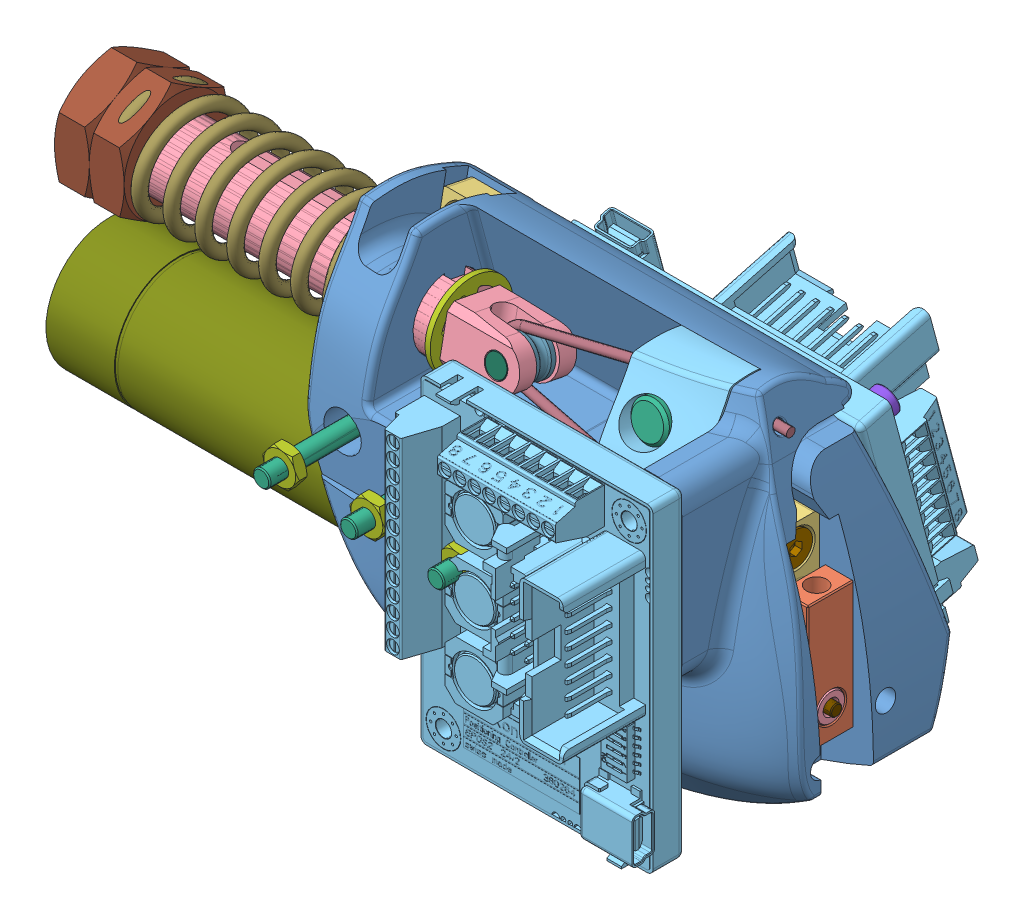
SolidWorks assembly a-antriebstrang-bein-rechts-v05, configuration Slave-BoardPosition 2. Lengths in mm.
Overall size (130.8 65.2 78.85).
43 component instances, 26 part files, 38 mates.
Components (placement in the parent):
- a-motorträger-beine-rechts-v01-1: a-motorträger-beine-rechts-v01 [01] x (-1 0 0) z (0 0 -1) size (130.38 65.2 41.28)
  - p-halterreferenz-rechts-v04-1: p-halterreferenz-rechts-v04 [01] at (-8 0 0) x (0 0 -1) z (1 0 0) size (41.28 65.2 84.36)
  - z-jfm-0608-06-v01-1: z-jfm-0608-06-v01 [01] at (-23.3 0 0) x (-1 0 0) z (0 0 -1) size (6 12 12)
  - z-induktiv-sensor-v01-1: z-induktiv-sensor-v01 [01] at (29 21.9082 7.6275) x (1 0 0) z (0 0.190809 -0.981627) size (8 16 4.7)
  - z-induktiv-sensor-v01-2: z-induktiv-sensor-v01 [01] at (-25.5 8.63 4) x (0 0 -1) z (-1 0 0) size (8 16 4.7)
  - p-federstössel-v01-1: p-federstössel-v01 [01] at (77.9 27.8 -1.72) x (-1 0 0) z (0 -0.190809 0.981627) size (77 12 12)
  - p-halterdeckel-rechts-v02-1: p-halterdeckel-rechts-v02 [01] at (-8 0 0) x (0 0 -1) z (1 0 0) size (28.27 33.45 14.71)
  - z-passschraube-misumi-4-v01-1: z-passschraube-misumi-4-v01 [01] at (-13.1 35.2829 -8.5672) x (0 -0.190809 0.981627) z (-0.839411 -0.533511 -0.103704) size (18 6.5 6.5)
  - z-passschraube-misumi-4-v01-2: z-passschraube-misumi-4-v01 [01] at (-13.1 16.1412 -12.288) x (0 -0.190809 0.981627) z (-0.58333 0.797312 0.154982) size (18 6.5 6.5)
  - Lock washer DIN 6799 - 7-11: Lock washer DIN 6799 - 7 [Lock washer DIN 6799 - 7] at (24 27.8 -1.72) x (0 0 1) z (-1 0 0) size (14.3 11.94 0.9)
  - Hexagon Nut ISO 4032 - M2.5 - W - N-19: Hexagon Nut ISO 4032 - M2.5 - W - N [Hexagon Nut ISO 4032 - M2.5 - W - N] at (-13.1 31.8991 8.8409) x (1 0 0) z (0 -0.190809 0.981627) size (5 5.77 2)
  - Hexagon Nut ISO 4032 - M2.5 - W - N-20: Hexagon Nut ISO 4032 - M2.5 - W - N [Hexagon Nut ISO 4032 - M2.5 - W - N] at (-13.1 12.7574 5.1202) x (1 0 0) z (0 -0.190809 0.981627) size (5 5.77 2)
  - DIN 7991 - M3 x 8 --- 4.8C-19: DIN 7991 - M3 x 8 --- 4.8C [DIN 7991 - M3 x 8 --- 4.8C] at (-30.15 20.63 0) size (8 5.7 5.7)
  - DIN 7991 - M3 x 8 --- 4.8C-20: DIN 7991 - M3 x 8 --- 4.8C [DIN 7991 - M3 x 8 --- 4.8C] at (33 34.5749 5.3527) x (0 -0.190809 0.981627) z (-0.981627 0.187303 0.036408) size (8 5.7 5.7)
  - p-oese-v01-1: p-oese-v01 [01] at (-25.5 37.4 0) size (3.5 4 4)
  - Hexagon Thin Nut ISO 4035 - M12 - N-19: Hexagon Thin Nut ISO 4035 - M12 - N [Hexagon Thin Nut ISO 4035 - M12 - N] at (74.9 27.8 -1.72) x (0 -0.006521 -0.999979) z (-1 0 0) size (18 20.78 6)
  - Hexagon Thin Nut ISO 4035 - M12 - N-20: Hexagon Thin Nut ISO 4035 - M12 - N [Hexagon Thin Nut ISO 4035 - M12 - N] at (80.9 27.8 -1.72) x (0 0 1) z (-1 0 0) size (18 20.78 6)
  - z-feder-febrotec-v01-1: z-feder-febrotec-v01 [01] at (40 28.171 -1.6479) x (1 0 0) z (0 -0.190809 0.981627) size (40.25 20.98 20.5)
  - p-seil-v02-1: p-seil-v02 [01] at (-16.85 -0.1381 -7.1506) x (-1 0 0) z (0 0.190809 -0.981627) size (48.5 39 1.5)
  - p-umlenkpulley-v06-1: p-umlenkpulley-v06 [01] at (-13.1 33.728 -0.5677) x (0 -0.190809 0.981627) z (-0.981627 0.187303 0.036408) size (3.6 7.15 7.15)
  - p-umlenkpulley-v06-4: p-umlenkpulley-v06 [01] at (-13.1 14.5863 -4.2885) x (0 -0.190809 0.981627) z (-0.997632 0.067518 0.013124) size (3.6 7.15 7.15)
  - p-umlenkpulley-v06-3: p-umlenkpulley-v06 [01] at (14.9 27.8 -1.72) x (0 -0.190809 0.981627) z (-0.981627 0.187303 0.036408) size (3.6 7.15 7.15)
  - Parallel Pin ISO 2338 - 4 h6 x 10 - St-11: Parallel Pin ISO 2338 - 4 h6 x 10 - St [Parallel Pin ISO 2338 - 4 h6 x 10 - St] at (14.9 28.754 -6.6281) x (0 -0.190809 0.981627) z (-0.981627 0.187303 0.036408) size (10 4 4)
- a-Maxon-EC22-386675-v01-2: a-Maxon-EC22-386675-v01 [01] at (-25.4 0 0) x (-1 0 0) z (0 0.342022 -0.939692) size (103.18 22 22)
  - z-Motor-Maxon-EC22-386673-v01-1: z-Motor-Maxon-EC22-386673-v01 [01] at origin size (73.23 22 22)
  - z-Getriebe-Maxon-GP22C_1-STUFIG-143972-v01-1: z-Getriebe-Maxon-GP22C_1-STUFIG-143972-v01 [01] at (-25.4 0 0) size (40.25 22 22)
- p-motorpulley-v04-2: p-motorpulley-v04 [01] at (3.15 0 0) x (1 0 0) z (0 0.939692 0.342022) size (35.05 9 9)
- DIN 913 - M2 x 3-C-10: DIN 913 - M2 x 3-C [DIN 913 - M2 x 3-C] at (10.15 4.2286 1.5391) x (0 -0.939692 -0.342022) z (1 0 0) size (3 2 2)
- p-absolutmess-plättchen-v04-2: p-absolutmess-plättchen-v04 [01] at (36.2 0 0) x (0 0 1) z (-1 0 0) size (8 22 5)
- ISO 2010 - M2.5 x 10 --- 10C-29: ISO 2010 - M2.5 x 10 --- 10C [ISO 2010 - M2.5 x 10 --- 10C] at (9 6.5778 2.3941) x (-1 0 0) z (0 -0.859497 -0.51114) size (10.59 4.7 4.66)
- ISO 2010 - M2.5 x 10 --- 10C-30: ISO 2010 - M2.5 x 10 --- 10C [ISO 2010 - M2.5 x 10 --- 10C] at (9 -5.3623 4.4995) x (-1 0 0) z (0 -0.924225 -0.381849) size (10.59 4.7 4.66)
- ISO 2010 - M2.5 x 10 --- 10C-31: ISO 2010 - M2.5 x 10 --- 10C [ISO 2010 - M2.5 x 10 --- 10C] at (9 -1.2155 -6.8937) x (-1 0 0) z (0 -0.959089 0.283105) size (10.59 4.7 4.66)
- p-gewindeeinsatz-v01-1: p-gewindeeinsatz-v01 [01] at (30.2 0 0) x (1 0 0) z (0 -0.998486 -0.054998) size (6 5 5)
- z-380264_epos2_24_2-v01-3: z-380264_epos2_24_2-v01 [01] at (9 10.5 22) x (0 1 0) z (1 0 0) size (55.21 20.01 40.39)
- z-380264_epos2_24_2-v01-2: z-380264_epos2_24_2-v01 [01] at (2 14.1149 -20.6087) x (1 0 0) z (0 0.965926 0.258819) size (55.21 20.01 40.39)
- z-zyl-schr-schaft-M3x40-v01-4: z-zyl-schr-schaft-M3x40-v01 [01] at (-2 15 -13) x (0 0 1) z (0.955009 0.296577 0) size (43 5.5 5.5)
- Hexagon Thin Nut ISO 4035 - M3 - C-11: Hexagon Thin Nut ISO 4035 - M3 - C [Hexagon Thin Nut ISO 4035 - M3 - C] at (-2 15 25) x (0.923728 0.383049 0) z (0 0 -1) size (5.5 6.35 1.8)
- z-zyl-schr-schaft-M3x40-v01-5: z-zyl-schr-schaft-M3x40-v01 [01] at (-17 15 -13) x (0 0 1) z (0.955009 0.296577 0) size (43 5.5 5.5)
- z-zyl-schr-schaft-M3x40-v01-6: z-zyl-schr-schaft-M3x40-v01 [01] at (-32 15 -13) x (0 0 1) z (0.955009 0.296577 0) size (43 5.5 5.5)
- Hexagon Thin Nut ISO 4035 - M3 - C-19: Hexagon Thin Nut ISO 4035 - M3 - C [Hexagon Thin Nut ISO 4035 - M3 - C] at (-17 15 25) x (0.923728 0.383049 0) z (0 0 -1) size (5.5 6.35 1.8)
- Hexagon Thin Nut ISO 4035 - M3 - C-20: Hexagon Thin Nut ISO 4035 - M3 - C [Hexagon Thin Nut ISO 4035 - M3 - C] at (-32 15 25) x (0.923728 0.383049 0) z (0 0 -1) size (5.5 6.35 1.8)
- n-zyl-schr-i6kt-M2.5x8 (BN11)-3: n-zyl-schr-i6kt-M2.5x8 (BN11) [n-zyl-schr-i6kt-M2.5x8 (BN11)] at (-21.5 -0.2788 -28.7101) x (0 -0.258819 0.965926) z (-0.965926 0.25 0.066987) size (10.5 4.5 4.5)
- n-zyl-schr-i6kt-M2.5x8 (BN11)-4: n-zyl-schr-i6kt-M2.5x8 (BN11) [n-zyl-schr-i6kt-M2.5x8 (BN11)] at (25.5 30.6309 -20.4279) x (0 -0.258819 0.965926) z (-0.793112 0.588322 0.15764) size (10.5 4.5 4.5)
Mates (geometry in assembly coordinates):
- Konzentrisch1: concentric aligned: cylinder of a-motorträger-beine-rechts-v01-1/p-halterreferenz-rechts-v04-1 through (0 0 0) axis (-1 0 0) radius 11.5; cylinder of a-Maxon-EC22-386675-v01-2/z-Getriebe-Maxon-GP22C_1-STUFIG-143972-v01-1 through (0 0 0) axis (-1 0 0) radius 11
- Deckungsgleich1: coincident anti-aligned: plane of a-motorträger-beine-rechts-v01-1/p-halterreferenz-rechts-v04-1 through (0 0 0) normal (-1 0 0); plane of a-Maxon-EC22-386675-v01-2/z-Getriebe-Maxon-GP22C_1-STUFIG-143972-v01-1 through (0 0 0) normal (1 0 0)
- Deckungsgleich2: coincident anti-aligned: plane of a-motorträger-beine-rechts-v01-1 through (0 0 0) normal (0 0 -1); plane of assembly through (0 0 0) normal (0 0 1)
- Deckungsgleich3: coincident aligned: plane of a-motorträger-beine-rechts-v01-1; plane of assembly through (0 0 0) normal (0 1 0)
- Deckungsgleich4: coincident anti-aligned: plane of a-motorträger-beine-rechts-v01-1 through (0 0 0) normal (-1 0 0); plane of assembly through (0 0 0) normal (1 0 0)
- Konzentrisch2: concentric aligned: cylinder of a-Maxon-EC22-386675-v01-2/z-Getriebe-Maxon-GP22C_1-STUFIG-143972-v01-1 through (14.85 0 0) axis (-1 0 0) radius 2; cylinder of p-motorpulley-v04-2 through (3.15 0 0) axis (-1 0 0) radius 2
- Deckungsgleich5: coincident anti-aligned: plane of a-Maxon-EC22-386675-v01-2/z-Getriebe-Maxon-GP22C_1-STUFIG-143972-v01-1 through (3.15 0 0) normal (1 0 0); plane of p-motorpulley-v04-2 through (3.15 1.5391 -4.2286) normal (-1 0 0)
- Konzentrisch3: concentric anti-aligned: cylinder of p-motorpulley-v04-2 through (10.15 0 0) axis (0 -0.939692 -0.342022) radius 0.8; cylinder of DIN 913 - M2 x 3-C-10 through (10.15 16.1627 5.8828) axis (0 0.939692 0.342022) radius 1
- Parallel2: parallel aligned: plane of a-Maxon-EC22-386675-v01-2/z-Getriebe-Maxon-GP22C_1-STUFIG-143972-v01-1 through (10.2 1.4095 0.513) normal (0 0.939692 0.342022); plane of p-motorpulley-v04-2 through (3.15 0 0) normal (0 0.939692 0.342022)
- Deckungsgleich7: coincident anti-aligned: plane of a-Maxon-EC22-386675-v01-2/z-Getriebe-Maxon-GP22C_1-STUFIG-143972-v01-1 through (10.2 1.4095 0.513) normal (0 0.939692 0.342022); plane of DIN 913 - M2 x 3-C-10 through (10.15 1.5805 0.0432) normal (0 -0.939692 -0.342022)
- Parallel3: parallel anti-aligned: plane of a-motorträger-beine-rechts-v01-1/p-halterreferenz-rechts-v04-1 through (42 0 -4.5) normal (0 0 1); plane of p-absolutmess-plättchen-v04-2 through (31.2 -5 -4) normal (0 0 -1)
- Abstand1: distance = 1 mm anti-aligned: plane of a-motorträger-beine-rechts-v01-1/z-induktiv-sensor-v01-2 through (30.2 8.63 -4) normal (1 0 0); plane of p-absolutmess-plättchen-v04-2 through (31.2 0 0) normal (-1 0 0)
- Konzentrisch5: concentric anti-aligned: cylinder of p-motorpulley-v04-2 through (3.15 0 0) axis (-1 0 0) radius 1; cylinder of p-absolutmess-plättchen-v04-2 through (31.2 0 0) axis (1 0 0) radius 2.5
- Konzentrisch6: concentric aligned: cylinder of a-motorträger-beine-rechts-v01-1/p-halterreferenz-rechts-v04-1 through (-42.3814 -5.3623 4.4995) axis (1 0 0) radius 1.5; cylinder of a-Maxon-EC22-386675-v01-2/z-Getriebe-Maxon-GP22C_1-STUFIG-143972-v01-1 through (-4 -5.3623 4.4995) axis (1 0 0) radius 1.025
- Konzentrisch29: concentric aligned: cylinder of a-motorträger-beine-rechts-v01-1/p-halterreferenz-rechts-v04-1 through (-42.3814 -5.3623 4.4995) axis (1 0 0) radius 1.5; cylinder of ISO 2010 - M2.5 x 10 --- 10C-30 through (24.875 -5.3623 4.4995) axis (1 0 0) radius 1.25
- Deckungsgleich16: coincident aligned: cone of a-motorträger-beine-rechts-v01-1/p-halterreferenz-rechts-v04-1 through (8 -5.3623 4.4995) axis (-1 0 0); cone of ISO 2010 - M2.5 x 10 --- 10C-30 through (8 -5.3623 4.4995) axis (-1 0 0)
- Konzentrisch31: concentric aligned: cylinder of a-motorträger-beine-rechts-v01-1/p-halterreferenz-rechts-v04-1 through (-42.3814 6.5778 2.3941) axis (1 0 0) radius 1.5; cylinder of ISO 2010 - M2.5 x 10 --- 10C-29 through (24.875 6.5778 2.3941) axis (1 0 0) radius 1.25
- Deckungsgleich17: coincident aligned: cone of a-motorträger-beine-rechts-v01-1/p-halterreferenz-rechts-v04-1 through (8 6.5778 2.3941) axis (-1 0 0); cone of ISO 2010 - M2.5 x 10 --- 10C-29 through (8 6.5778 2.3941) axis (-1 0 0)
- Konzentrisch33: concentric aligned: cylinder of a-motorträger-beine-rechts-v01-1/p-halterreferenz-rechts-v04-1 through (-42.3814 -1.2155 -6.8937) axis (1 0 0) radius 1.5; cylinder of ISO 2010 - M2.5 x 10 --- 10C-31 through (24.875 -1.2155 -6.8937) axis (1 0 0) radius 1.25
- Deckungsgleich18: coincident aligned: cone of a-motorträger-beine-rechts-v01-1/p-halterreferenz-rechts-v04-1 through (8 -1.2155 -6.8937) axis (-1 0 0); cone of ISO 2010 - M2.5 x 10 --- 10C-31 through (8 -1.2155 -6.8937) axis (-1 0 0)
- Konzentrisch318: concentric anti-aligned: cylinder of p-absolutmess-plättchen-v04-2 through (31.2 0 0) axis (1 0 0) radius 2.5; cylinder of p-gewindeeinsatz-v01-1 through (30.2 0 0) axis (-1 0 0) radius 2.5
- Deckungsgleich150: coincident aligned: plane of p-absolutmess-plättchen-v04-2 through (36.2 0 0) normal (1 0 0); plane of p-gewindeeinsatz-v01-1 through (36.2 -0.0275 0.4992) normal (1 0 0)
- Konzentrisch324: concentric anti-aligned: cylinder of a-motorträger-beine-rechts-v01-1/p-halterreferenz-rechts-v04-1 through (-2 15 -22.5327) axis (0 0 -1) radius 2; cylinder of z-zyl-schr-schaft-M3x40-v01-4 through (-2 15 12) axis (0 0 1) radius 1.5
- Deckungsgleich162: coincident anti-aligned: plane of a-motorträger-beine-rechts-v01-1/p-halterreferenz-rechts-v04-1 through (0 15 9) normal (0 0 1); plane of z-zyl-schr-schaft-M3x40-v01-4
- Konzentrisch325: concentric aligned: cylinder of z-zyl-schr-schaft-M3x40-v01-4 through (-2 15 -13) axis (0 0 -1) radius 1.5; cylinder of Hexagon Thin Nut ISO 4035 - M3 - C-11 through (-2 15 26.8) axis (0 0 -1) radius 1.25
- Abstand2: distance = 35 mm anti-aligned: plane of Hexagon Thin Nut ISO 4035 - M3 - C-11 through (-7.0805 12.8932 25) normal (0 0 -1); plane of z-zyl-schr-schaft-M3x40-v01-4 through (-1.1844 12.3737 -10) normal (0 0 1)
- Konzentrisch326: concentric aligned: cylinder of a-motorträger-beine-rechts-v01-1/p-halterreferenz-rechts-v04-1 through (-2 15 -22.5327) axis (0 0 -1) radius 2; cylinder of z-zyl-schr-schaft-M3x40-v01-4 through (-2 15 -13) axis (0 0 -1) radius 1.5
- Deckungsgleich163: coincident anti-aligned: plane of a-motorträger-beine-rechts-v01-1/p-halterreferenz-rechts-v04-1 through (1.25 15 -10) normal (0 0 -1); plane of z-zyl-schr-schaft-M3x40-v01-4 through (-1.1844 12.3737 -10) normal (0 0 1)
- Deckungsgleich165: coincident anti-aligned: plane of z-380264_epos2_24_2-v01-2 through (2 13.0796 -16.745) normal (0 -0.258819 0.965926); plane of a-motorträger-beine-rechts-v01-1/p-halterreferenz-rechts-v04-1 through (8 5.0624 -18.8932) normal (0 0.258819 -0.965926)
- Konzentrisch327: concentric aligned: cylinder of a-motorträger-beine-rechts-v01-1/p-halterreferenz-rechts-v04-1 through (-21.5 -13.657 21.2181) axis (0 0.258819 -0.965926) radius 0.9; cylinder of z-380264_epos2_24_2-v01-2 through (-21.5 -0.9258 -26.2953) axis (0 0.258819 -0.965926) radius 1.35
- Konzentrisch328: concentric aligned: cylinder of a-motorträger-beine-rechts-v01-1/p-halterreferenz-rechts-v04-1 through (25.5 26.2089 -3.9248) axis (0 0.258819 -0.965926) radius 0.9; cylinder of z-380264_epos2_24_2-v01-2 through (25.5 29.9838 -18.0131) axis (0 0.258819 -0.965926) radius 1.35
- Deckungsgleich166: coincident anti-aligned: plane of a-motorträger-beine-rechts-v01-1/p-halterreferenz-rechts-v04-1 through (28.5 37.5 18) normal (0 0 1); plane of z-380264_epos2_24_2-v01-3 through (9 10.5 18) normal (0 0 -1)
- Konzentrisch329: concentric aligned: cylinder of a-motorträger-beine-rechts-v01-1/p-halterreferenz-rechts-v04-1 through (25 34 8) axis (0 0 1) radius 0.9; cylinder of z-380264_epos2_24_2-v01-3 through (25 34 23.6) axis (0 0 1) radius 1.35
- Konzentrisch330: concentric aligned: cylinder of a-motorträger-beine-rechts-v01-1/p-halterreferenz-rechts-v04-1 through (-7 -13 8) axis (0 0 1) radius 0.9; cylinder of z-380264_epos2_24_2-v01-3 through (-7 -13 23.6) axis (0 0 1) radius 1.35
- Konzentrisch331: concentric aligned: cylinder of z-380264_epos2_24_2-v01-2 through (25.5 29.9838 -18.0131) axis (0 0.258819 -0.965926) radius 1.35; cylinder of n-zyl-schr-i6kt-M2.5x8 (BN11)-4 through (25.5 38.8484 -51.0961) axis (0 0.258819 -0.965926) radius 1.25
- Deckungsgleich167: coincident anti-aligned: plane of z-380264_epos2_24_2-v01-2 through (25.5 29.9838 -18.0131) normal (0 0.258819 -0.965926); plane of n-zyl-schr-i6kt-M2.5x8 (BN11)-4 through (26.8704 31.7075 -17.5512) normal (0 -0.258819 0.965926)
- Konzentrisch332: concentric aligned: cylinder of z-380264_epos2_24_2-v01-2 through (-21.5 -0.9258 -26.2953) axis (0 0.258819 -0.965926) radius 1.35; cylinder of n-zyl-schr-i6kt-M2.5x8 (BN11)-3 through (-21.5 7.9387 -59.3783) axis (0 0.258819 -0.965926) radius 1.25
- Deckungsgleich168: coincident aligned: plane of z-380264_epos2_24_2-v01-2 through (-21.5 -0.9258 -26.2953) normal (0 0.258819 -0.965926); circle of n-zyl-schr-i6kt-M2.5x8 (BN11)-3
